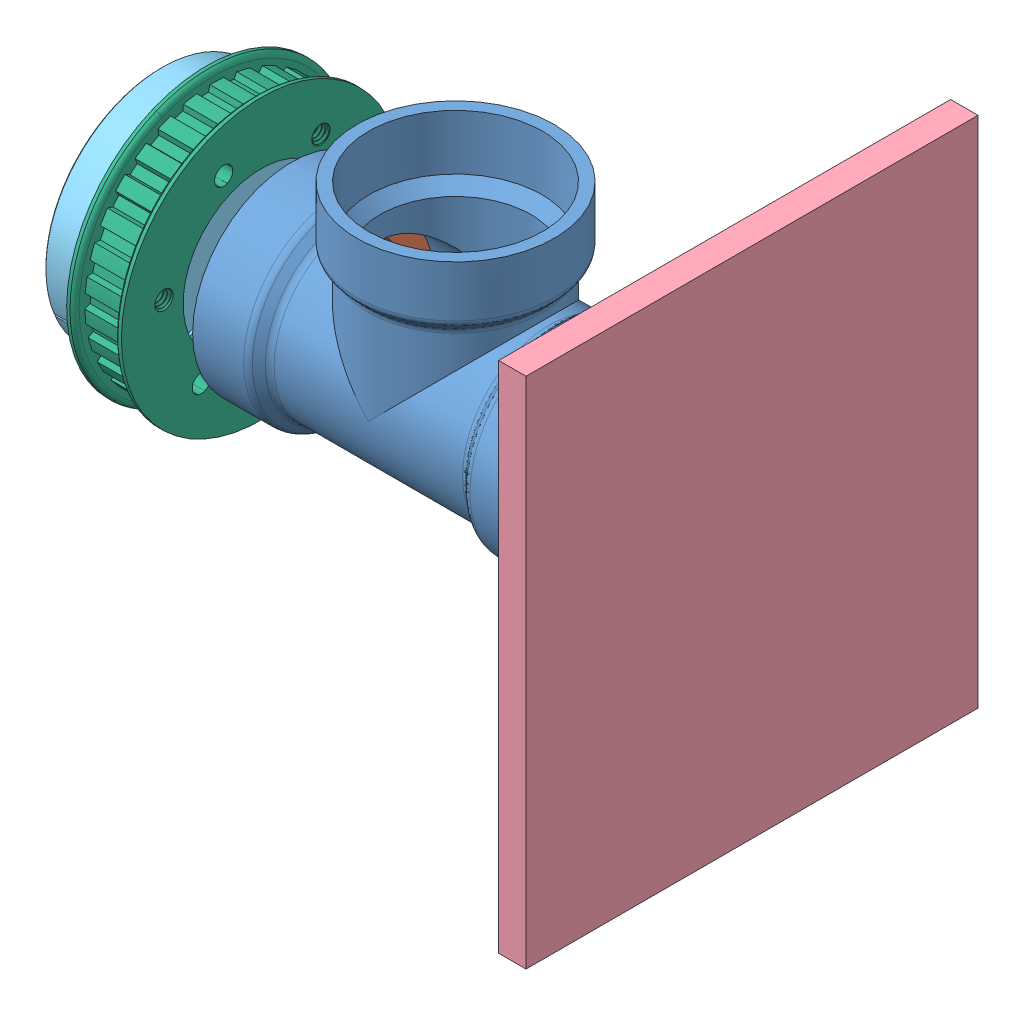
SolidWorks assembly Rotator Head, configuration Default. Lengths in mm.
Overall size (205.74 178.66 157.29).
10 component instances, 8 part files, 17 mates.
Components (placement in the parent):
- 1608T155_STANDARD-WALL BLACK ABS PIPE   PIPE FITTING-1: 1608T155_STANDARD-WALL BLACK ABS PIPE   PIPE FITTING [1608T155] at (70.0151 51.5982 78.7717) size (114.3 91.5 68.71)
- Bearing_Bushing_2-1: Bearing_Bushing_2 [Default] at (128.4351 51.5982 78.7717) x (0 -0.381849 0.924225) z (0 -0.924225 -0.381849) size (61.1 20.32 61.1)
- Bearing_Bushing_2-2: Bearing_Bushing_2 [Default] at (11.5951 51.5982 78.7717) x (0 0.381849 -0.924225) z (0 -0.924225 -0.381849) size (61.1 20.32 61.1)
- 6455K140_GENERAL PURPOSE PLASTIC BALL BEARING-1: 6455K140_GENERAL PURPOSE PLASTIC BALL BEARING [6455K14] at (121.7851 51.5982 78.7717) x (0 -0.160705 0.987003) z (-1 0 0) size (50.8 50.8 12.7)
- 6455K140_GENERAL PURPOSE PLASTIC BALL BEARING-2: 6455K140_GENERAL PURPOSE PLASTIC BALL BEARING [6455K14] at (18.2451 51.5982 78.7717) x (0 -0.932635 -0.360822) z (1 0 0) size (50.8 50.8 12.7)
- Delrin Shaft-2: Delrin Shaft [Default] at (-32.5549 51.5982 78.7717) x (0 0 -1) z (1 0 0) size (157.29 178.66 205.74)
- 6086K321_QUICK-DISCONNECT BUSHING-1: 6086K321_QUICK-DISCONNECT BUSHING [6086K321] at (-32.5549 51.5982 78.7717) x (0 0.924225 0.381849) z (-1 0 0) size (80.96 80.96 34.92)
- 6495K217_TIMING BELT PULLEY.step-1: 6495K217_TIMING BELT PULLEY.step [Default] at (-7.1549 51.5982 78.7717) x (0 -0.924225 -0.381849) z (1 0 0) size (97.28 97.28 19.05)
- 95649A130_UHMW POLYETHYLENE FLAT WASHER-1: 95649A130_UHMW POLYETHYLENE FLAT WASHER [95649A130] at (128.1351 51.5982 78.7717) x (0 -1 0) z (0 0 1) size (44.45 3.3 44.45)
- 91395A230_FIBERGLASS HEX NUT-1: 91395A230_FIBERGLASS HEX NUT [91395A230] at (141.74 51.5982 78.7717) x (0 0.99482 0.10165) z (0 -0.10165 0.99482) size (33.34 21.33 38.49)
Mates (geometry in assembly coordinates):
- Concentric1: concentric anti-aligned: cone of 1608T155_STANDARD-WALL BLACK ABS PIPE   PIPE FITTING-1 through (108.1151 51.5982 78.7717) axis (-1 0 0); cylinder of Bearing_Bushing_2-1 through (108.1151 51.5982 78.7717) axis (1 0 0) radius 30.55
- Coincident1: coincident aligned: circle of 1608T155_STANDARD-WALL BLACK ABS PIPE   PIPE FITTING-1; plane of Bearing_Bushing_2-1 through (108.1151 51.5982 78.7717) normal (-1 0 0)
- Concentric2: concentric anti-aligned: cone of 1608T155_STANDARD-WALL BLACK ABS PIPE   PIPE FITTING-1 through (31.9151 51.5982 78.7717) axis (1 0 0); cylinder of Bearing_Bushing_2-2 through (31.9151 51.5982 78.7717) axis (-1 0 0) radius 30.55
- Coincident2: coincident anti-aligned: circle of 1608T155_STANDARD-WALL BLACK ABS PIPE   PIPE FITTING-1; plane of Bearing_Bushing_2-2 through (31.9151 51.5982 78.7717) normal (1 0 0)
- Concentric3: concentric anti-aligned: cylinder of Bearing_Bushing_2-2 through (24.5951 51.5982 78.7717) axis (-1 0 0) radius 25.404; cylinder of 6455K140_GENERAL PURPOSE PLASTIC BALL BEARING-2 through (24.5951 51.5982 78.7717) axis (1 0 0) radius 25.4
- Coincident3: coincident anti-aligned: plane of Bearing_Bushing_2-2 through (24.5951 51.5982 78.7717) normal (-1 0 0); plane of 6455K140_GENERAL PURPOSE PLASTIC BALL BEARING-2 through (24.5951 60.534 55.675) normal (1 0 0)
- Concentric4: concentric anti-aligned: cylinder of Bearing_Bushing_2-1 through (115.4351 51.5982 78.7717) axis (1 0 0) radius 25.404; cylinder of 6455K140_GENERAL PURPOSE PLASTIC BALL BEARING-1 through (115.4351 51.5982 78.7717) axis (-1 0 0) radius 25.4
- Coincident4: coincident anti-aligned: plane of Bearing_Bushing_2-1 through (115.4351 51.5982 78.7717) normal (1 0 0); plane of 6455K140_GENERAL PURPOSE PLASTIC BALL BEARING-1 through (115.4351 76.0414 82.7515) normal (-1 0 0)
- Concentric7: concentric anti-aligned: cylinder of 6455K140_GENERAL PURPOSE PLASTIC BALL BEARING-2 through (24.5951 51.5982 78.7717) axis (1 0 0) radius 12.7; cylinder of Delrin Shaft-2 through (125.5601 51.5982 78.7717) axis (-1 0 0) radius 12.7
- Coincident5: coincident anti-aligned: plane of 6455K140_GENERAL PURPOSE PLASTIC BALL BEARING-2 through (11.8951 56.4098 66.335) normal (-1 0 0); plane of Delrin Shaft-2 through (11.8951 51.5982 78.7717) normal (1 0 0)
- Coincident6: coincident aligned: cone of 6086K321_QUICK-DISCONNECT BUSHING-1 through (-16.6799 51.5982 78.7717) axis (1 0 0); cone of 6495K217_TIMING BELT PULLEY.step-1 through (2.3701 51.5982 78.7717) axis (1 0 0)
- Coincident7: coincident aligned: plane of Delrin Shaft-2 through (-32.5549 51.5982 78.7717) normal (-1 0 0); plane of 6086K321_QUICK-DISCONNECT BUSHING-1 through (-32.5549 57.6601 64.0996) normal (-1 0 0)
- Parallel2: parallel anti-aligned: plane of 6086K321_QUICK-DISCONNECT BUSHING-1 through (-19.8549 61.901 53.8351) normal (1 0 0); plane of 6495K217_TIMING BELT PULLEY.step-1 through (-16.6799 33.0247 123.7269) normal (-1 0 0)
- Concentric9: concentric anti-aligned: cylinder of Delrin Shaft-2 through (163.6601 51.5982 78.7717) axis (-1 0 0) radius 11.0172; cylinder of 95649A130_UHMW POLYETHYLENE FLAT WASHER-1 through (128.1351 51.5982 78.7717) axis (1 0 0) radius 11.8745
- Coincident9: coincident anti-aligned: plane of 6455K140_GENERAL PURPOSE PLASTIC BALL BEARING-1 through (128.1351 64.7599 80.9147) normal (1 0 0); plane of 95649A130_UHMW POLYETHYLENE FLAT WASHER-1 through (128.1351 51.5982 78.7717) normal (-1 0 0)
- Concentric10: concentric anti-aligned: cylinder of Delrin Shaft-2 through (163.6601 51.5982 78.7717) axis (-1 0 0) radius 11.0172; circle of 91395A230_FIBERGLASS HEX NUT-1
- Coincident10: coincident anti-aligned: plane of 95649A130_UHMW POLYETHYLENE FLAT WASHER-1 through (131.4371 51.5982 78.7717) normal (1 0 0); plane of 91395A230_FIBERGLASS HEX NUT-1 through (131.4371 51.5982 78.7717) normal (-1 0 0)
